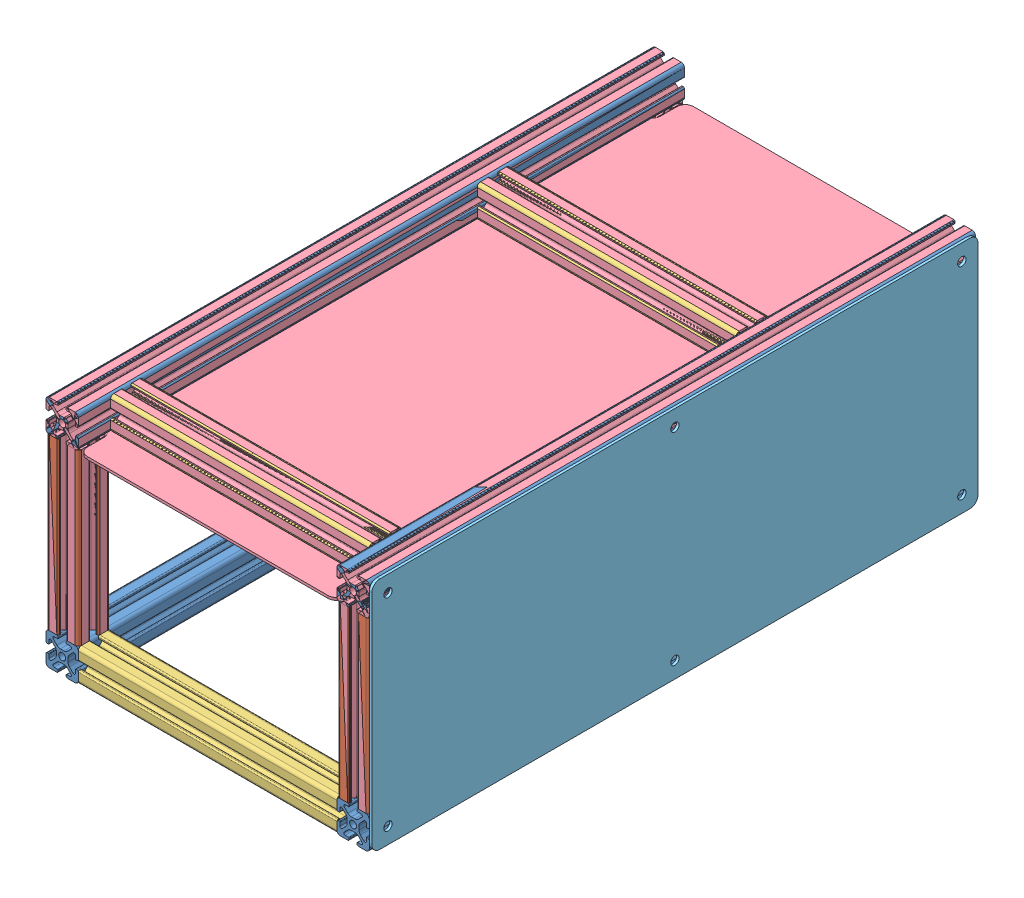
SolidWorks assembly UOR23-ARM-3-A-000_ARM_Module, configuration Default. Lengths in mm.
Overall size (201.57 144.98 375).
14 component instances, 5 part files, 24 mates.
Components (placement in the parent):
- UOR23-ARM-3-P-001-4: UOR23-ARM-3-P-001 [Default] at (-89.9949 -62.4949 0) size (19.99 19.99 375)
- UOR23-ARM-3-P-001-7: UOR23-ARM-3-P-001 [Default] at (-89.9949 62.4949 0) size (19.99 19.99 375)
- UOR23-ARM-3-P-002-1: UOR23-ARM-3-P-002 [Default] at (-89.9949 0 177.5051) x (1 0 0) z (0 -1 0) size (19.99 19.99 105)
- UOR23-ARM-3-P-003-1: UOR23-ARM-3-P-003 [Default] at (0 -62.4949 177.5051) x (0 0 1) z (-1 0 0) size (19.99 19.99 160)
- UOR23-ARM-3-P-003-4: UOR23-ARM-3-P-003 [Default] at (0 -62.4949 -177.5051) x (0 0 -1) z (1 0 0) size (19.99 19.99 160)
- UOR23-ARM-3-P-002-2: UOR23-ARM-3-P-002 [Default] at (-89.9949 0 -177.5051) x (1 0 0) z (0 1 0) size (19.99 19.99 105)
- UOR23-ARM-3-P-002-3: UOR23-ARM-3-P-002 [Default] at (89.9949 0 -177.5051) x (-1 0 0) z (0 -1 0) size (19.99 19.99 105)
- UOR23-ARM-3-P-001-8: UOR23-ARM-3-P-001 [Default] at (89.9949 62.4949 0) x (-1 0 0) z (0 0 -1) size (19.99 19.99 375)
- UOR23-ARM-3-P-002-4: UOR23-ARM-3-P-002 [Default] at (89.9949 0 177.5051) x (-1 0 0) z (0 1 0) size (19.99 19.99 105)
- UOR23-ARM-3-P-001-9: UOR23-ARM-3-P-001 [Default] at (89.9949 -62.4949 0) x (-1 0 0) z (0 0 -1) size (19.99 19.99 375)
- UOR23-ARM-3-P-003-6: UOR23-ARM-3-P-003 [Default] at (0 62.4949 157.5051) x (0 1 0) z (1 0 0) size (19.99 19.99 160)
- UOR23-ARM-3-P-003-7: UOR23-ARM-3-P-003 [Default] at (0 62.4949 -69.3151) x (0 0 -1) z (1 0 0) size (19.99 19.99 160)
- UOR23-ARM-3-P-005_Top_Panel-1: UOR23-ARM-3-P-005_Top_Panel [Default] at origin size (199.98 124.99 375)
- UOR23-ARM-3-P-004_Front_Panel-1: UOR23-ARM-3-P-004_Front_Panel [Default] at origin size (1.59 144.98 375)
Mates (geometry in assembly coordinates):
- Coincident1: coincident anti-aligned: plane of UOR22-ARM-3-P-001-4 through (-97.9832 -52.5 187.5) normal (0 1 0); plane of UOR22-ARM-3-P-002-1 through (-91.1283 -52.5 184.1302) normal (0 -1 0)
- Coincident2: coincident aligned: plane of UOR22-ARM-3-P-001-4 through (-91.1283 -55.8698 187.5) normal (0 0 1); plane of UOR22-ARM-3-P-002-1 through (-82.0066 -52.5 187.5) normal (0 0 1)
- Coincident3: coincident aligned: plane of UOR22-ARM-3-P-001-4 through (-80 -54.5066 187.5) normal (1 0 0); plane of UOR22-ARM-3-P-002-1 through (-80 -52.5 185.4934) normal (1 0 0)
- Coincident4: coincident anti-aligned: plane of UOR22-ARM-3-P-001-4 through (-80 -70.4832 187.5) normal (1 0 0); plane of UOR22-ARM-3-P-003-1 through (-80 -55.8698 176.3717) normal (-1 0 0)
- Coincident5: coincident aligned: plane of UOR22-ARM-3-P-001-4 through (-91.1283 -55.8698 187.5) normal (0 0 1); plane of UOR22-ARM-3-P-003-1 through (-80 -70.4832 187.5) normal (0 0 1)
- Coincident6: coincident aligned: plane of UOR22-ARM-3-P-001-4 through (-82.0066 -72.4898 187.5) normal (0 -1 0); plane of UOR22-ARM-3-P-003-1 through (-80 -72.4898 185.4934) normal (0 -1 0)
- Coincident10: coincident aligned: plane of UOR22-ARM-3-P-001-7 through (-91.1283 69.12 187.5) normal (0 0 1); plane of UOR22-ARM-3-P-002-1 through (-97.9832 -52.5 187.5) normal (0 0 1)
- Coincident11: coincident anti-aligned: plane of UOR22-ARM-3-P-001-7 through (-97.9832 52.5 187.5) normal (0 -1 0); plane of UOR22-ARM-3-P-002-1 through (-91.1283 52.5 184.1302) normal (0 1 0)
- Coincident12: coincident aligned: plane of UOR22-ARM-3-P-001-7 through (-80 54.5066 187.5) normal (1 0 0); plane of UOR22-ARM-3-P-002-1 through (-80 -52.5 185.4934) normal (1 0 0)
- Coincident13: coincident aligned: plane of UOR22-ARM-3-P-001-4 through (-89.9949 -62.4949 0) normal (0 0 1)
- Coincident14: coincident anti-aligned: plane of UOR22-ARM-3-P-002-1 through (-89.9949 0 177.5051) normal (0 -1 0)
- Coincident15: coincident anti-aligned: plane of UOR22-ARM-3-P-003-1 through (0 -62.4949 177.5051) normal (-1 0 0)
- Coincident16: coincident anti-aligned: plane of UOR22-ARM-3-P-001-8 through (99.9898 54.5066 -187.5) normal (1 0 0); plane of UOR22-ARM-3-P-004_Front_Panel-1 through (99.9898 -10.0102 0) normal (-1 0 0)
- Width1: width aligned: plane of UOR22-ARM-3-P-004_Front_Panel-1 through (99.9898 -92.5102 -210) normal (0 0 -1); plane of UOR22-ARM-3-P-002-3 through (99.9898 -92.5102 210) normal (0 0 1); plane of UOR22-ARM-3-P-004_Front_Panel-1 through (97.9832 -52.5 -187.5) normal (0 0 -1); plane of UOR22-ARM-3-P-002-4 through (97.9832 52.5 187.5) normal (0 0 1)
- Coincident17: coincident aligned: plane of UOR22-ARM-3-P-004_Front_Panel-1 through (99.9898 72.4898 -210) normal (0 1 0); plane of UOR22-ARM-3-P-001-8 through (97.9832 72.4898 -187.5) normal (0 1 0)
- Coincident18: coincident anti-aligned: plane of UOR22-ARM-3-P-001-7 through (-82.0066 72.4898 187.5) normal (0 1 0); plane of UOR22-ARM-3-P-005_Top_Panel-1 through (-0.0102 72.4898 0) normal (0 -1 0)
- Coincident19: coincident anti-aligned: plane of UOR22-ARM-3-P-005_Top_Panel-1 through (-0.0102 72.4898 0) normal (0 0 -1)
- Coincident20: coincident anti-aligned: plane of UOR22-ARM-3-P-004_Front_Panel-1 through (99.9898 -10.0102 0) normal (-1 0 0); plane of UOR22-ARM-3-P-005_Top_Panel-1 through (99.9898 74.0778 -210) normal (1 0 0)
- Coincident21: coincident anti-aligned: plane of UOR22-ARM-3-P-001-8 through (80 54.5066 -187.5) normal (-1 0 0); plane of UOR22-ARM-3-P-003-6 through (80 61.3615 164.1302) normal (1 0 0)
- Coincident22: coincident aligned: plane of UOR22-ARM-3-P-001-8 through (82.0066 52.5 -187.5) normal (0 -1 0); plane of UOR22-ARM-3-P-003-6 through (80 52.5 165.4934) normal (0 -1 0)
- Distance1: distance = 20 mm aligned: plane of UOR22-ARM-3-P-003-6 through (80 70.4832 167.5) normal (0 0 1); plane of UOR22-ARM-3-P-001-8 through (91.1283 69.12 187.5) normal (0 0 1)
- Coincident24: coincident anti-aligned: plane of UOR22-ARM-3-P-001-8 through (80 54.5066 -187.5) normal (-1 0 0); plane of UOR22-ARM-3-P-003-7 through (80 69.12 -68.1817) normal (1 0 0)
- Coincident25: coincident aligned: plane of UOR22-ARM-3-P-001-8 through (82.0066 52.5 -187.5) normal (0 -1 0); plane of UOR22-ARM-3-P-003-7 through (80 52.5 -77.3034) normal (0 -1 0)
- Distance2: distance = 246.81 mm anti-aligned: plane of UOR22-ARM-3-P-003-7 through (80 54.5066 -79.31) normal (0 0 -1); plane of UOR22-ARM-3-P-003-6 through (80 54.5066 167.5) normal (0 0 1)
